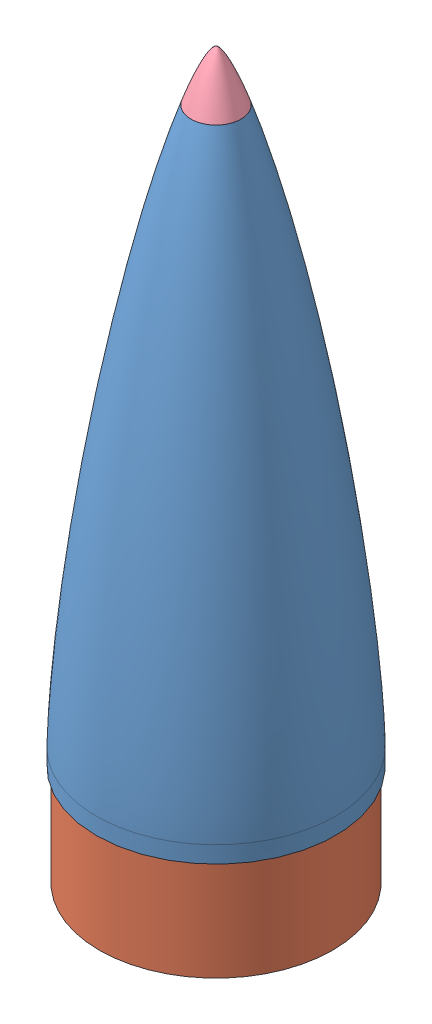
SolidWorks assembly Von Karman Assembly, configuration Default. Lengths in mm.
Overall size (180.97 547.72 180.97).
5 component instances, 5 part files, 4 mates.
Components (placement in the parent):
- Von Karman NoseCone-1: Von Karman NoseCone [Default] x (0 -1 0) z (0 0 1) size (433.41 180.97 180.97)
- NoseCone Coupler-3: NoseCone Coupler [Default] at (0 -546.1 0) size (177.8 88.9 177.8)
- Von Karman NoseCone Base-3: Von Karman NoseCone Base [Default] at (0 0 0) x (0 -1 0) z (0 0 1) size (19.05 45.77 45.77)
- Von Karman NoseCone Tip-2: Von Karman NoseCone Tip [Default] x (0 -1 0) z (0 0 1) size (38.1 37.72 37.72)
- 3014T450_STEEL EYEBOLT WITH SHOULDER - FOR LIFTING-2: 3014T450_STEEL EYEBOLT WITH SHOULDER - FOR LIFTING [3014T45] at (0.3283 -77.729 0.094) x (-1 0 0) z (0 0 1) size (30.16 64.79 14.29)
Mates (geometry in assembly coordinates):
- Coincident10: coincident: circle of Von Karman NoseCone-1; circle of NoseCone Coupler-3
- Coincident12: coincident: circle of Von Karman NoseCone-1; circle of Von Karman NoseCone Base-3
- Coincident13: coincident: circle of Von Karman NoseCone-1; circle of Von Karman NoseCone Tip-2
- Tangent1: tangent: circle of Von Karman NoseCone Base-3; curve of 3014T450_STEEL EYEBOLT WITH SHOULDER - FOR LIFTING-2
